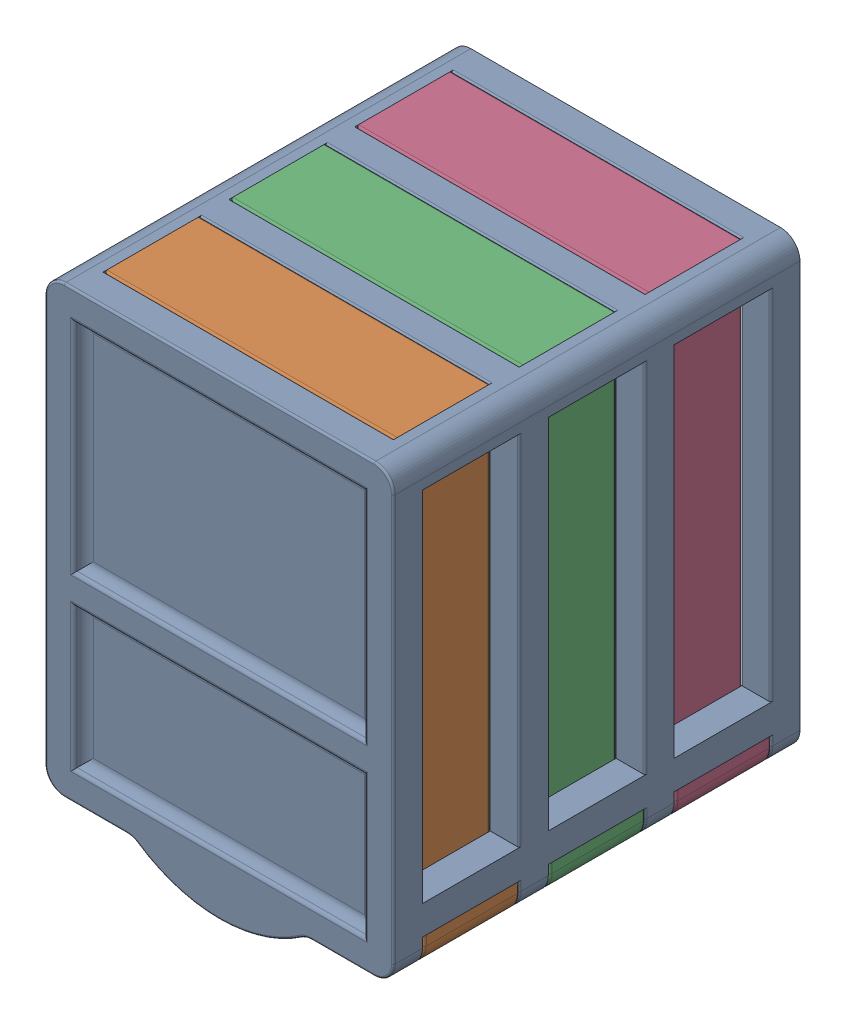
SolidWorks assembly FINAL AM, configuration Default. Lengths in mm.
Overall size (270 367.05 315).
4 component instances, 2 part files, 9 mates.
Components (placement in the parent):
- BASE  -1: BASE   [Default] at origin size (270 367.05 315)
- DRAWER-1: DRAWER [Default] at (-149.9967 218.1019 163.2095) x (-1 0 0) z (0 0 1) size (270 365.49 73.5)
- DRAWER-2: DRAWER [Default] at (-149.9967 218.1019 65.7095) x (-1 0 0) z (0 0 1) size (270 365.49 73.5)
- DRAWER-3: DRAWER [Default] at (-149.9967 218.1019 -31.7905) x (-1 0 0) z (0 0 1) size (270 365.49 73.5)
Mates (geometry in assembly coordinates):
- Coincident3: coincident anti-aligned: plane of BASE-1 through (-75 21.003 155.9734) normal (0 0 1); plane of DRAWER-1 through (-187.5 275.5513 155.9734) normal (0 0 -1)
- Coincident5: coincident anti-aligned: plane of BASE-1 through (37.5 275.5513 230.9734) normal (-1 0 0); plane of DRAWER-1 through (37.5 275.5513 229.4734) normal (1 0 0)
- Coincident7: coincident aligned: plane of DRAWER-1 through (-187.5 275.5513 229.4734) normal (-1 0 0); plane of DRAWER-2 through (-187.5 275.5513 131.9734) normal (-1 0 0)
- Coincident9: coincident anti-aligned: plane of BASE-1 through (-75 21.003 58.4734) normal (0 0 1); plane of DRAWER-2 through (-187.5 275.5513 58.4734) normal (0 0 -1)
- Coincident10: coincident aligned: plane of DRAWER-2 through (-187.5 275.5513 131.9734) normal (-1 0 0); plane of DRAWER-3 through (-187.5 275.5513 34.4734) normal (-1 0 0)
- Coincident12: coincident anti-aligned: plane of BASE-1 through (-75 21.003 -39.0266) normal (0 0 1); plane of DRAWER-3 through (-187.5 275.5513 -39.0266) normal (0 0 -1)
- LimitDistance1: limit distance = 0 mm anti-aligned: plane of BASE-1 through (-210 -46.9487 230.9734) normal (0 -1 0); plane of DRAWER-1 through (-187.5 -46.9487 155.9734) normal (0 1 0)
- LimitDistance2: limit distance = 0 mm anti-aligned: plane of BASE-1 through (-210 -46.9487 133.4734) normal (0 -1 0); plane of DRAWER-2 through (-187.5 -46.9487 58.4734) normal (0 1 0)
- LimitDistance3: limit distance = 0 mm anti-aligned: plane of DRAWER-3 through (-187.5 -46.9487 -39.0266) normal (0 1 0); plane of BASE-1 through (-187.5 -46.9487 35.9734) normal (0 -1 0)
